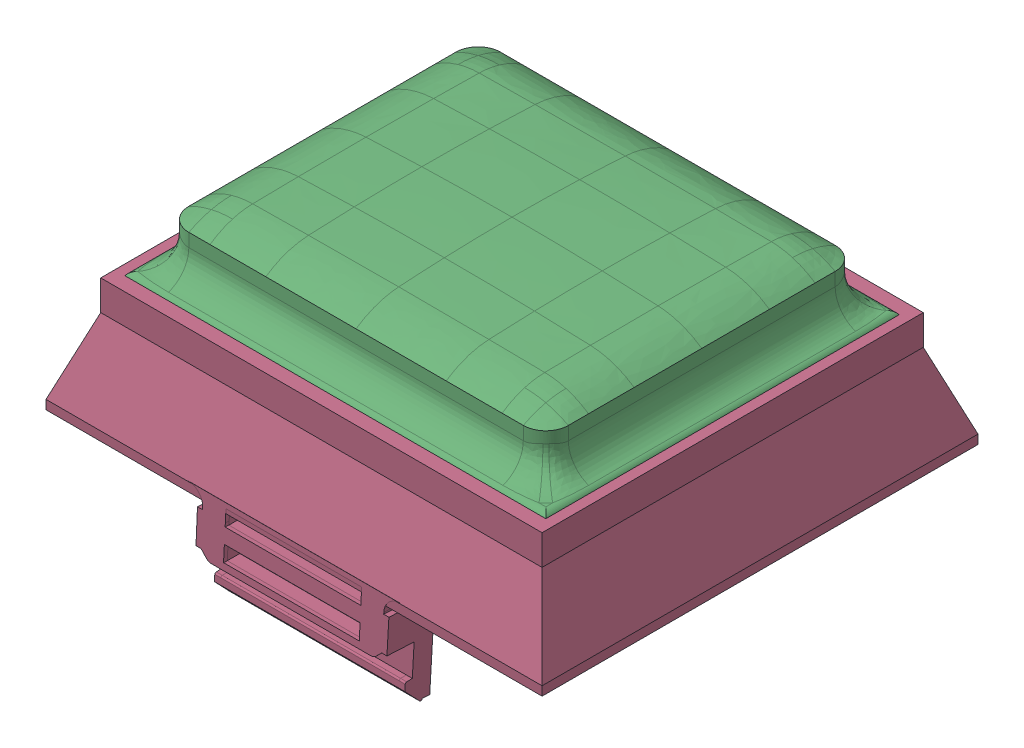
SolidWorks assembly Original, configuration 默认. Lengths in mm.
Overall size (33 18.27 29.5).
4 component instances, 4 part files, 10 mates.
Components (placement in the parent):
- lensall-1: lensall [默认] at origin size (28.33 2.18 23.83)
- InsideSkin-1: InsideSkin [默认] at (0.0001 0 0.2499) size (23.8 5.48 19.29)
- Topskin-1: Topskin [默认] at (0.0001 2 0.2499) size (28.02 6.25 23.52)
- SupportBase-2: SupportBase [默认] at origin size (33 14.02 29.5)
Mates (geometry in assembly coordinates):
- 同心2: concentric anti-aligned: cylinder of InsideSkin-1 through (10.8751 17.7531 8.6249) axis (0 1 0) radius 0.7; cylinder of Board3Con1612611OriginalSkin_TOP-1 through (10.8751 24 8.6249) axis (0 -1 0) radius 0.7
- 同心3: concentric anti-aligned: cylinder of InsideSkin-1 through (10.8751 17.7531 -9.1251) axis (0 1 0) radius 0.7; cylinder of Board3Con1612611OriginalSkin_TOP-1 through (10.8751 24 -9.1251) axis (0 -1 0) radius 0.7
- 重合4: coincident aligned: plane of InsideSkin-1 through (10.8751 19 -9.1251) normal (0 -1 0); plane of Board3Con1612611OriginalSkin_TOP-1 through (0.0001 19 0.2499) normal (0 -1 0)
- 重合6: coordinate: point of SupportBase-2
- 重合7: coincident anti-aligned: plane of lensall-1 through (13.75 19 -11.5) normal (0.939693 0.34202 0); plane of SupportBase-2 through (13.75 19 12.7803) normal (-0.939693 -0.34202 0)
- 同心5: concentric aligned: cylinder of lensall-1 through (13.3294 18.6938 -11.0794) axis (-0.323616 0.889126 0.323616) radius 0.5; cylinder of SupportBase-2 through (10.7866 25.6801 -8.5366) axis (-0.323616 0.889126 0.323616) radius 0.5
- 重合8: coincident anti-aligned: plane of lensall-1 through (0 18 0) normal (0 -1 0); plane of SupportBase-2 through (0 18 0) normal (0 1 0)
- 重合9: coincident anti-aligned: plane of lensall-1 through (0 19 0) normal (0 1 0); plane of Board3Con1612611OriginalSkin_TOP-1 through (0.0001 19 0.2499) normal (0 -1 0)
- 重合10: coincident anti-aligned: plane of Board3Con1612611OriginalSkin_TOP-1 through (0.0001 19 11.7499) normal (0 0 1); plane of SupportBase-2 through (-13.5999 21 11.7499) normal (0 0 -1)
- 重合11: coincident anti-aligned: plane of Board3Con1612611OriginalSkin_TOP-1 through (14.0001 19 0.2499) normal (1 0 0); plane of SupportBase-2 through (14.0001 21 11.7499) normal (-1 0 0)
